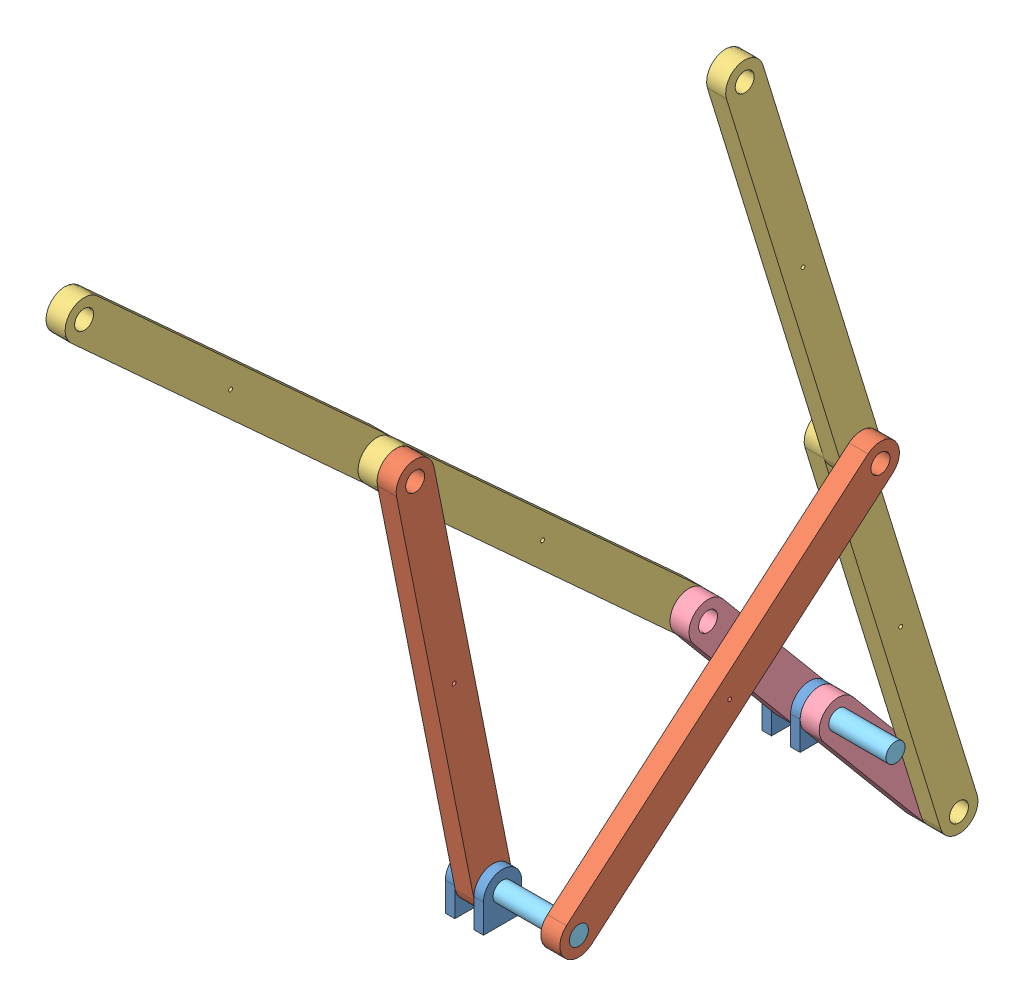
SolidWorks assembly Caminante, configuration Predeterminado. Lengths in mm.
Overall size (75 436.12 441.86).
12 component instances, 5 part files, 26 mates.
Components (placement in the parent):
- apoyo-1: apoyo [Predeterminado] at (-4.4574 0.7359 25) size (20 25 20)
- apoyo-2: apoyo [Predeterminado] at (-4.4574 0.7359 191) size (20 25 20)
- ab-1: ab [Predeterminado] at (-4.4574 105.2133 211.4109) x (0 -0.980552 -0.196259) z (-1 0 0) size (228 20 10)
- BC-1: BC [Predeterminado] at (-14.4574 137.0404 155.0434) x (0 0.674523 0.738254) z (1 0 0) size (228 20 10)
- oa-1: oa [Predeterminado] at (-4.4574 35.0629 51.6325) x (0 0.766917 0.641746) z (-1 0 0) size (103 20 10)
- BC-3: BC [Predeterminado] at (-24.4574 277.3411 308.6002) x (0 0.674523 0.738254) z (-1 0 0) size (228 20 10)
- Eje_2-1: Eje_2 [Predeterminado] at (-14.4574 3.2359 25) x (0 0 -1) z (1 0 0) size (10 10 60)
- oa-2: oa [Predeterminado] at (10.5426 -28.5912 -1.6325) x (0 0.766917 0.641746) z (-1 0 0) size (103 20 10)
- BC-4: BC [Predeterminado] at (20.5426 38.9847 2.3137) x (0 0.955797 0.294026) z (1 0 0) size (228 20 10)
- BC-5: BC [Predeterminado] at (30.5426 237.7906 63.4711) x (0 0.955797 0.294026) z (1 0 0) size (228 20 10)
- Eje_2-2: Eje_2 [Predeterminado] at (-14.4574 3.2359 191) x (0 0 -1) z (1 0 0) size (10 10 60)
- ab-2: ab [Predeterminado] at (40.5426 70.8118 111.9462) x (0 -0.649768 0.760133) z (-1 0 0) size (228 20 10)
Mates (geometry in assembly coordinates):
- Coincidente2: coincident: plane of apoyo-1 through (-4.4574 0.7359 25) normal (1 0 0); plane of apoyo-2 through (-4.4574 0.7359 191) normal (1 0 0)
- Distancia1: distance = 166 mm: plane of apoyo-1 through (-4.4574 0.7359 25) normal (0 0 1); plane of apoyo-2 through (-4.4574 0.7359 191) normal (0 0 1)
- Coincidente7: coincident: circle of apoyo-1; circle of oa-1
- Coincidente8: coincident: circle of BC-1; circle of oa-1
- Coincidente10: coincident: circle of ab-1; circle of BC-1
- Coincidente12: coincident: circle of apoyo-2; circle of ab-1
- Coincidente17: coincident: circle of BC-1; circle of BC-3
- Paralelo3: parallel: plane of BC-1 through (-9.4574 74.2725 71.5197) normal (0 0.738254 -0.674523); plane of BC-3 through (-29.4574 214.5733 225.0765) normal (0 0.738254 -0.674523)
- Concéntrica1: concentric: cylinder of oa-1 through (-9.4574 3.2359 25) axis (1 0 0) radius 5; cylinder of Eje_2-1 through (45.5426 3.2359 25) axis (-1 0 0) radius 5
- Coincidente18: coincident: circle of apoyo-1; circle of Eje_2-1
- Coincidente19: coincident: cylinder of Eje_2-1 through (45.5426 3.2359 25) axis (-1 0 0) radius 5; circle of oa-2
- Coincidente22: coincident: circle of oa-2; circle of BC-4
- Coincidente23: coincident: circle of BC-4; circle of BC-5
- Concéntrica2: concentric: cylinder of ab-1 through (-9.4574 3.2359 191) axis (1 0 0) radius 5; cylinder of Eje_2-2 through (45.5426 3.2359 191) axis (-1 0 0) radius 5
- Coincidente24: coincident: circle of apoyo-2; circle of Eje_2-2
- Coincidente25: coincident: circle of BC-5; circle of ab-2
- Concéntrica3: concentric: cylinder of Eje_2-2 through (45.5426 3.2359 191) axis (-1 0 0) radius 5; cylinder of ab-2 through (35.5426 3.2359 191) axis (1 0 0) radius 5
- Coincidente27: coincident: circle of apoyo-1; circle of oa-2
- Concéntrica4: concentric: cylinder of Eje_2-2 through (45.5426 3.2359 191) axis (-1 0 0) radius 5; cylinder of ab-2 through (35.5426 3.2359 191) axis (1 0 0) radius 5
- Paralelo4: parallel: plane of BC-4 through (25.5426 -63.3585 -18.707) normal (0 -0.294026 0.955797); plane of BC-5 through (35.5426 135.4474 42.4504) normal (0 -0.294026 0.955797)
- Coincidente32: coincident: plane of apoyo-1 through (-4.4574 0.7359 25) normal (0 1 0); plane of apoyo-2 through (-4.4574 0.7359 191) normal (0 1 0)
- Paralelo7: parallel: plane of oa-1 through (-4.4574 35.0629 51.6325) normal (-1 0 0); plane of Eje_2-1 through (-14.4574 3.2359 25) normal (1 0 0)
- Paralelo8: parallel: plane of Eje_2-1 through (-14.4574 3.2359 25) normal (1 0 0); plane of oa-2 through (10.5426 -28.5912 -1.6325) normal (-1 0 0)
- Paralelo9: parallel: plane of oa-1 through (-4.4574 35.0629 51.6325) normal (-1 0 0); plane of oa-2 through (10.5426 -28.5912 -1.6325) normal (-1 0 0)
- Coincidente36: coincident: plane of oa-1 through (-4.4574 35.0629 51.6325) normal (0 0.641746 -0.766917); plane of oa-2 through (10.5426 -28.5912 -1.6325) normal (0 0.641746 -0.766917)
- Paralelo10: parallel: plane of oa-1 through (-4.4574 35.0629 51.6325) normal (0 0.766917 0.641746); plane of oa-2 through (10.5426 -28.5912 -1.6325) normal (0 0.766917 0.641746)
